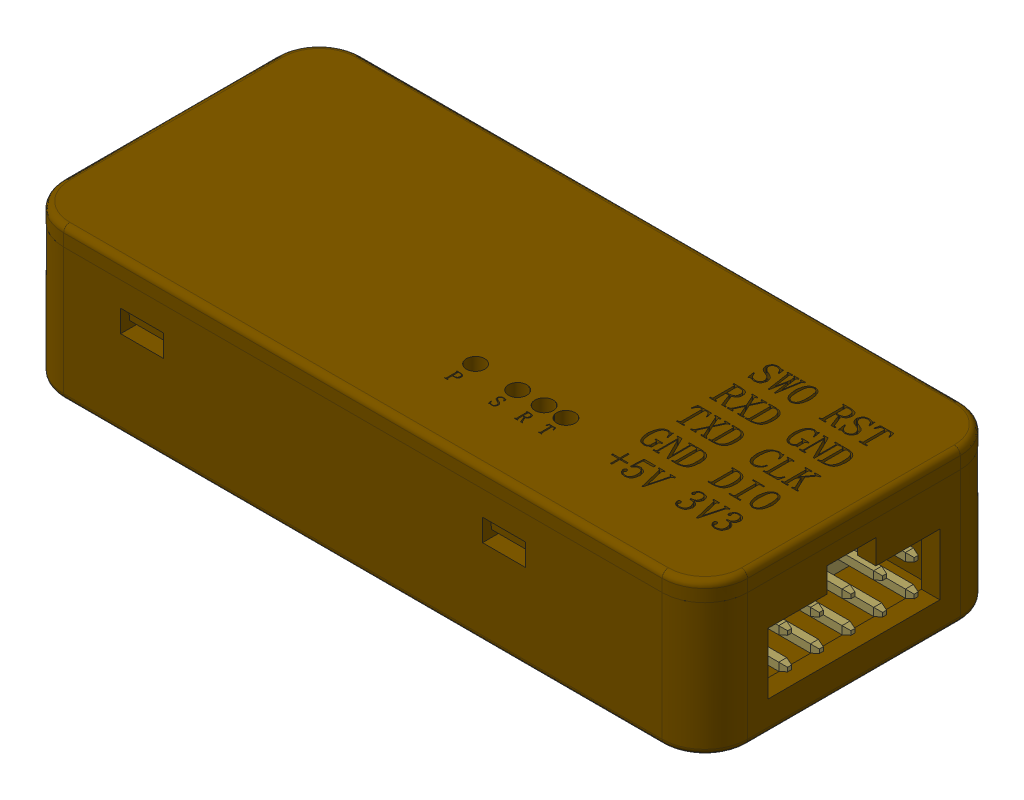
SolidWorks assembly stlink, configuration 默认. Lengths in mm.
Overall size (55.74 12.36 24.3).
53 component instances, 19 part files, 2 mates.
Components (placement in the parent):
- 3D_ST-LINK  V2-1_1_2025-01-13-1: 3D_ST-LINK  V2-1_1_2025-01-13 [默认] at (-26.0347 24.2157 75.3483) x (1 0 0) z (0 1 0) size (53.96 20.88 11.97)
  - 3D_ST-LINK  V2-1_1_2025-01-13.step-1: 3D_ST-LINK  V2-1_1_2025-01-13.step [默认] at origin size (53.96 20.88 11.97)
    - S64j-U1-SOT-23-5_L3.0-W1.7-P0.95-LS2.8-BR.step-1: S64j-U1-SOT-23-5_L3.0-W1.7-P0.95-LS2.8-BR.step [默认] at (18.5179 2.032 1.6) x (-1 0 0) z (0 0 1) size (2.89 2.78 1.2)
      - COMPOUND.step-1: COMPOUND.step [默认] at origin size (2.89 2.78 1.2)
    - S64j-Q1-SOT-23(SOT-23-3).step-1: S64j-Q1-SOT-23(SOT-23-3).step [默认] at (12.319 6.604 1.6) x (-1 0 0) z (0 0 1) size (3.01 2.92 1.27)
      - COMPOUND-0.step-1: COMPOUND-0.step [默认] at origin size (3.01 2.92 1.27)
    - S64j-LED1-LED-ARRAY-SMD_4P-L1.6-W1.5-TR-RD_TJ-S1615SW6TGLCRB-A5.step-1: S64j-LED1-LED-ARRAY-SMD_4P-L1.6-W1.5-TR-RD_TJ-S1615SW6TGLCRB-A5.step [默认] at (31.8771 5.334 1.6) x (0 -1 0) z (0 0 1) size (1.62 1.51 0.61)
      - COMPOUND-1.step-1: COMPOUND-1.step [默认] at origin size (1.62 1.51 0.61)
    - S64j-C1-CASE-A_3216.step-1: S64j-C1-CASE-A_3216.step [默认] at (12.446 2.921 1.6) x (0 -1 0) z (0 0 1) size (3.2 1.6 1.7)
      - COMPOUND-2.step-1: COMPOUND-2.step [默认] at origin size (3.2 1.6 1.7)
    - S64j-Board.step-1: S64j-Board.step [默认] at origin size (45.82 20.88 1.6)
    - S64j-R12-R0603.step-1: S64j-R12-R0603.step [默认] at (35.8141 2.286 1.6) x (0 1 0) z (0 0 1) size (1.6 0.8 0.8)
    - S64j-R12-R0603.step-2: S64j-R12-R0603.step [默认] at (34.0361 2.286 1.6) x (0 1 0) z (0 0 1) size (1.6 0.8 0.8)
    - S64j-R12-R0603.step-3: S64j-R12-R0603.step [默认] at (29.8451 2.2946 1.6) x (0 1 0) z (0 0 1) size (1.6 0.8 0.8)
    - S64j-R12-R0603.step-4: S64j-R12-R0603.step [默认] at (14.859 14.732 1.6) x (0 1 0) z (0 0 1) size (1.6 0.8 0.8)
    - S64j-R12-R0603.step-5: S64j-R12-R0603.step [默认] at (28.9561 18.796 1.6) size (1.6 0.8 0.8)
    - S64j-R12-R0603.step-6: S64j-R12-R0603.step [默认] at (26.0351 18.796 1.6) size (1.6 0.8 0.8)
    - S64j-R12-R0603.step-7: S64j-R12-R0603.step [默认] at (29.8451 5.461 1.6) x (0 -1 0) z (0 0 1) size (1.6 0.8 0.8)
    - S64j-R12-R0603.step-8: S64j-R12-R0603.step [默认] at (25.1461 5.461 1.6) x (0 1 0) z (0 0 1) size (1.6 0.8 0.8)
    - S64j-R12-R0603.step-9: S64j-R12-R0603.step [默认] at (18.161 5.461 1.6) x (0 -1 0) z (0 0 1) size (1.6 0.8 0.8)
    - S64j-R12-R0603.step-10: S64j-R12-R0603.step [默认] at (14.859 5.461 1.6) x (0 -1 0) z (0 0 1) size (1.6 0.8 0.8)
    - S64j-R12-R0603.step-11: S64j-R12-R0603.step [默认] at (21.844 5.4696 1.6) x (0 -1 0) z (0 0 1) size (1.6 0.8 0.8)
    - S64j-R12-R0603.step-12: S64j-R12-R0603.step [默认] at (16.51 5.461 1.6) x (0 -1 0) z (0 0 1) size (1.6 0.8 0.8)
    - S64j-R12-R0603.step-13: S64j-R12-R0603.step [默认] at (19.685 5.461 1.6) x (0 1 0) z (0 0 1) size (1.6 0.8 0.8)
    - S64j-R12-R0603.step-14: S64j-R12-R0603.step [默认] at (9.906 13.208 1.6) x (0 -1 0) z (0 0 1) size (1.6 0.8 0.8)
    - S64j-R12-R0603.step-15: S64j-R12-R0603.step [默认] at (9.906 6.985 1.6) x (0 1 0) z (0 0 1) size (1.6 0.8 0.8)
    - S64j-R12-R0603.step-16: S64j-R12-R0603.step [默认] at (26.6701 5.461 1.6) x (0 1 0) z (0 0 1) size (1.6 0.8 0.8)
    - S64j-R12-R0603.step-17: S64j-R12-R0603.step [默认] at (9.906 9.906 1.6) x (0 -1 0) z (0 0 1) size (1.6 0.8 0.8)
    - S64j-R12-R0603.step-18: S64j-R12-R0603.step [默认] at (34.9251 18.796 1.6) size (1.6 0.8 0.8)
    - S64j-R12-R0603.step-19: S64j-R12-R0603.step [默认] at (12.2027 12.2134 1.6) size (1.6 0.8 0.8)
    - S64j-R12-R0603.step-20: S64j-R12-R0603.step [默认] at (12.1844 10.668 1.6) size (1.6 0.8 0.8)
    - S64j-R22-R0603.step-1: S64j-R22-R0603.step [默认] at (22.352 18.796 1.6) x (-1 0 0) z (0 0 1) size (1.6 0.8 0.8)
    - S64j-R12-R0603.step-21: S64j-R12-R0603.step [默认] at (28.3211 2.286 1.6) x (0 1 0) z (0 0 1) size (1.6 0.8 0.8)
    - S64j-C2-C0603.step-1: S64j-C2-C0603.step [默认] at (14.859 2.286 1.6) x (0 1 0) z (0 0 1) size (1.6 0.8 0.8)
    - S64j-C2-C0603.step-2: S64j-C2-C0603.step [默认] at (22.225 2.286 1.6) x (0 1 0) z (0 0 1) size (1.6 0.8 0.8)
    - S64j-C5-C0603.step-1: S64j-C5-C0603.step [默认] at (31.7501 12.573 1.6) x (0 -1 0) z (0 0 1) size (1.6 0.8 0.8)
    - S64j-C2-C0603.step-3: S64j-C2-C0603.step [默认] at (32.0041 18.796 1.6) size (1.6 0.8 0.8)
    - S64j-C2-C0603.step-4: S64j-C2-C0603.step [默认] at (18.923 18.796 1.6) x (-1 0 0) z (0 0 1) size (1.6 0.8 0.8)
    - S64j-C2-C0603.step-5: S64j-C2-C0603.step [默认] at (14.859 9.525 1.6) x (0 -1 0) z (0 0 1) size (1.6 0.8 0.8)
    - S64j-C2-C0603.step-6: S64j-C2-C0603.step [默认] at (23.495 5.461 1.6) x (0 1 0) z (0 0 1) size (1.6 0.8 0.8)
    - S64j-C2-C0603.step-7: S64j-C2-C0603.step [默认] at (28.1941 14.224 1.6) x (0 1 0) z (0 0 1) size (1.6 0.8 0.8)
    - S64j-C2-C0603.step-8: S64j-C2-C0603.step [默认] at (24.003 2.286 1.6) x (0 1 0) z (0 0 1) size (1.6 0.8 0.8)
    - S64j-C5-C0603.step-2: S64j-C5-C0603.step [默认] at (31.7501 9.525 1.6) x (0 1 0) z (0 0 1) size (1.6 0.8 0.8)
    - S64j-X1-OSC-SMD_L5.0-W3.2.step-1: S64j-X1-OSC-SMD_L5.0-W3.2.step [默认] at (34.5548 11.0631 1.6) x (0 -1 0) z (0 0 1) size (5 3.2 1.21)
    - S64j-H2-HDR-TH_4P-P2.54-V-M.step-1: S64j-H2-HDR-TH_4P-P2.54-V-M.step [默认] at (10.033 18.796 1.6) x (-1 0 0) z (0 0 1) size (10.17 2.66 11.54) (hidden)
    - S64j-USB1-USB-3.1-SMD_U262-161N-4BVC11.step-1: S64j-USB1-USB-3.1-SMD_U262-161N-4BVC11.step [默认] at (5.334 10.414 1.6) x (0 -1 0) z (0 0 1) size (8.94 7.9 4.1)
    - S64j-H3-HDR-TH_SMD-10P-P2.54.step-1: S64j-H3-HDR-TH_SMD-10P-P2.54.step [默认] at (42.7991 10.541 1.6) size (11.68 12.9 5.16)
    - S64j-LED2-LED0603.step-1: S64j-LED2-LED0603.step [默认] at (28.3211 5.461 1.6) x (0 -1 0) z (0 0 1) size (1.62 0.8 0.6)
    - S64j-U2-LQFP-48_L7.0-W7.0-P0.50-LS9.0-BL.step-1: S64j-U2-LQFP-48_L7.0-W7.0-P0.50-LS9.0-BL.step [默认] at (21.4566 12.446 1.6) x (0 1 0) z (0 0 1) size (9 9 1.5)
    - S64j-LED3-LED0603.step-1: S64j-LED3-LED0603.step [默认] at (34.0361 5.334 1.6) x (0 -1 0) z (0 0 1) size (1.62 0.8 0.6)
    - S64j-LED4-LED0603.step-1: S64j-LED4-LED0603.step [默认] at (35.8141 5.334 1.6) x (0 -1 0) z (0 0 1) size (1.62 0.8 0.6)
    - S64j-F1-F1206.step-1: S64j-F1-F1206.step [默认] at (8.8113 3.048 1.6) size (3.2 1.7 0.6)
- stlink-1: stlink [默认] at (-26.0353 19.9657 75.3489) size (55.74 12.36 24.3)
Mates (geometry in assembly coordinates):
- 重合1: coincident anti-aligned: plane of 3D_ST-LINK  V2-1_1_2025-01-13-1/3D_ST-LINK  V2-1_1_2025-01-13.step-1/S64j-Board.step-1 through (-3.1099 24.2157 64.7704) normal (0 -1 0); plane of stlink-1 through (-26.0353 24.2157 75.3489) normal (0 1 0)
- 同心1: concentric aligned: cylinder of 3D_ST-LINK  V2-1_1_2025-01-13-1/3D_ST-LINK  V2-1_1_2025-01-13.step-1/S64j-Board.step-1 through (-24.2541 24.2157 73.4433) axis (0 -1 0) radius 0.5766; axis of stlink-1 through (-24.2541 30.8157 73.4433) axis (0 -1 0)
